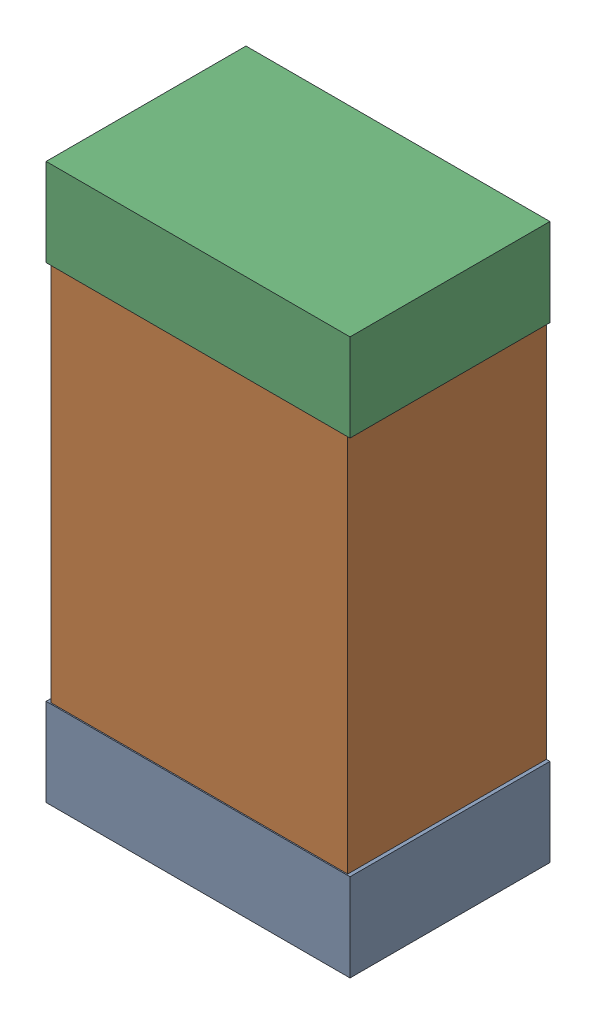
SolidWorks assembly C5Kanaloa_v2.0.0_GPIO_b_1, configuration Default. Lengths in mm.
Overall size (1.3 2.38 0.85).
6 component instances, 2 part files, 0 mates.
Components (placement in the parent):
- 330415056-1: 330415056 [Default] at (48.26 35.83 0) size (1.3 0.38 0.85)
  - Extruded_2-1: Extruded_2 [Default] at origin size (1.3 0.38 0.85)
- 352877008-1: 352877008 [Default] at (48.26 36.83 0) size (1.27 2.2 0.85)
  - Extruded_3-1: Extruded_3 [Default] at origin size (1.27 2.2 0.85)
- 330415056-2: 330415056 [Default] at (48.26 37.83 0) size (1.3 0.38 0.85)
  - Extruded_2-1: Extruded_2 [Default] at origin size (1.3 0.38 0.85)
